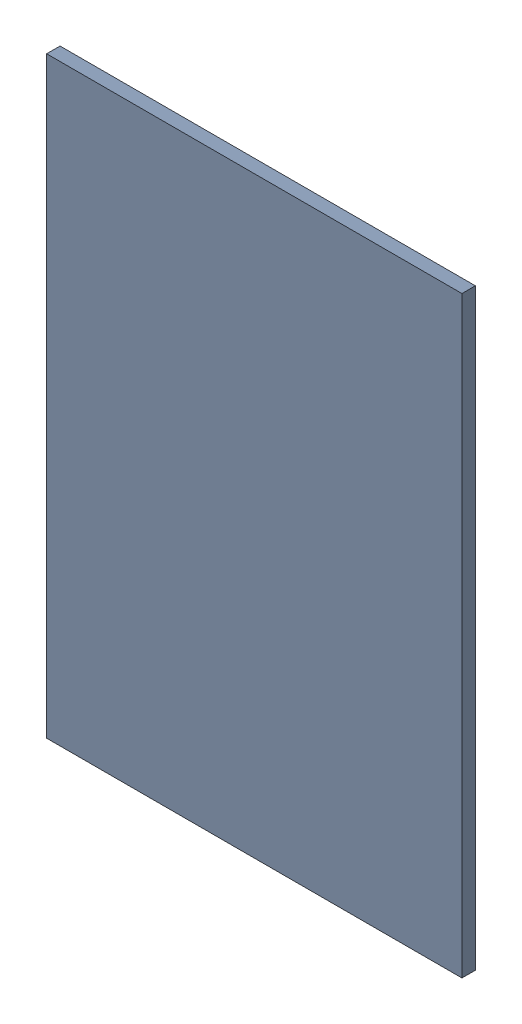
SolidWorks assembly Pad C1-2(27.19mm,46mm) on Top Layer, configuration Predeterminado. Lengths in mm.
Overall size (1.1 1.57 0.04).
2 component instances, 1 part files, 0 mates.
Components (placement in the parent):
- Pad C1-2(27.19mm,46mm) on Top Layer-1-1: Pad C1-2(27.19mm,46mm) on Top Layer-1 [Predeterminado] at (-68.317 -44.187 -0.0457) size (1.1 1.57 0.04)
  - Pad C1-2(27.19mm,46mm) on Top Layer-Part-1-1: Pad C1-2(27.19mm,46mm) on Top Layer-Part-1 [Predeterminado] at origin size (1.1 1.57 0.04)
